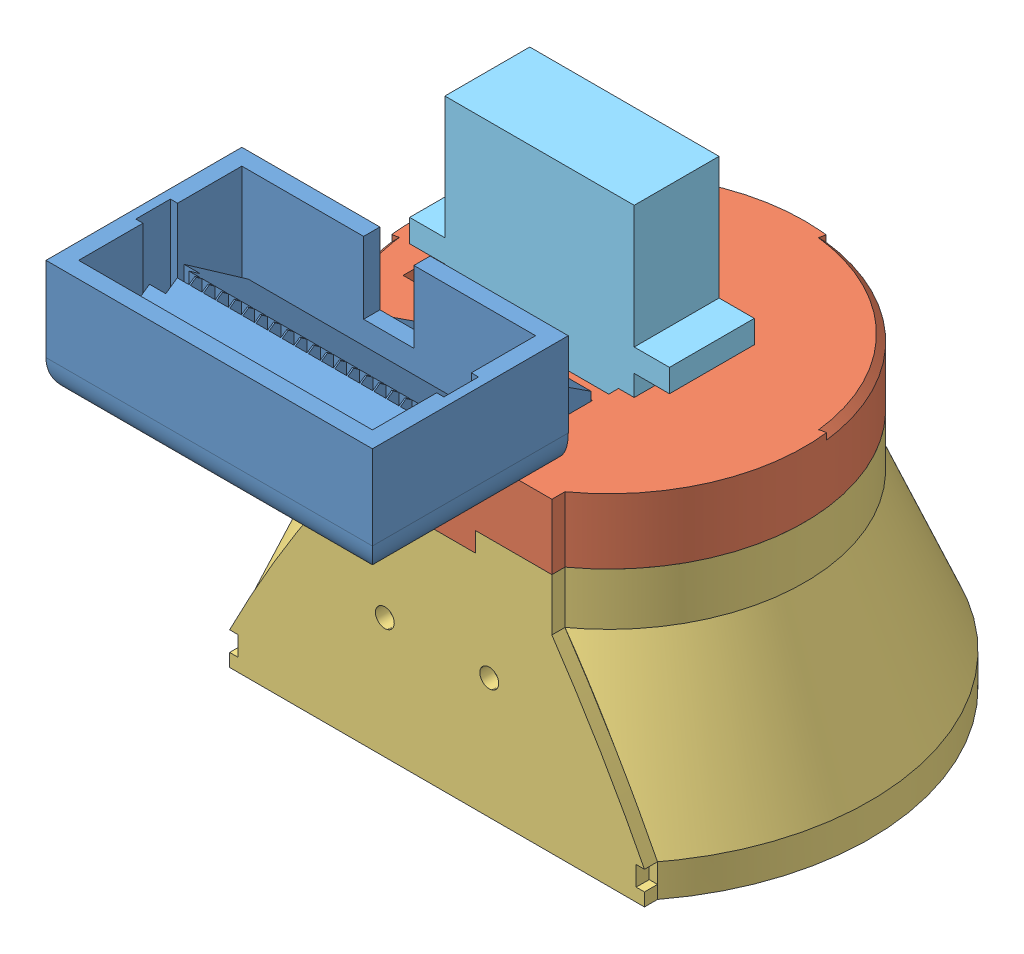
SolidWorks assembly funnelTrough, configuration Default. Lengths in mm.
Overall size (80 74.75 101.15).
5 component instances, 5 part files, 11 mates.
Components (placement in the parent):
- trough-1: trough [Default] at (-6.9672 -29.6533 -31.125) size (50.1 31 51.05)
- funnelMotorMount-1: funnelMotorMount [Default] at (-6.8672 -28.4033 -35.125) size (60 13.05 56.3)
- funnel-1: funnel [Default] at (-6.8672 -28.4033 -35.125) size (80 37 68.48)
- irShield-1: irShield [Default] at (10.2328 -3.1712 10.975) x (0 0 -1) z (1 0 0) size (5 3.9 2.54)
- servoOutline_micro-1: servoOutline_micro [Default] at (-10.9672 -7.9033 -28.625) x (0 0 -1) z (-1 0 0) size (13 35.3 39.8)
Mates (geometry in assembly coordinates):
- Coincident10: coincident: plane of trough-1 through (28.2088 -17.2758 -25.025) normal (0 0 -1); plane of funnelMotorMount-1 through (-6.8672 -21.6533 -25.025) normal (0 0 1)
- Coincident11: coincident: plane of trough-1 through (28.2088 -21.6533 -25.025) normal (0 -1 0); plane of funnelMotorMount-1 through (-6.8672 -21.6533 -35.125) normal (0 1 0)
- Coincident12: coincident: plane of trough-1 through (-14.4672 -12.1141 -15.2118) normal (-1 0 0); plane of funnelMotorMount-1 through (-14.4672 -21.6533 -35.125) normal (1 0 0)
- Coincident13: coincident: plane of funnelMotorMount-1 through (-6.8672 -28.4033 -35.125) normal (0 -1 0); plane of funnel-1 through (-6.8672 -28.4033 -35.125) normal (0 1 0)
- Coincident14: coincident: plane of funnelMotorMount-1 through (-0.9927 -31.4033 -8.825) normal (1 0 0); plane of funnel-1 through (-0.9927 -31.4033 -8.825) normal (-1 0 0)
- Coincident15: coincident: plane of funnelMotorMount-1 through (8.8746 -76.1936 -8.825) normal (0 0 1); plane of funnel-1 through (-175.0684 -162.3647 -8.825) normal (0 0 1)
- Parallel1: parallel: plane of trough-1 through (12.0328 -8.5533 10.975) normal (-1 0 0); plane of irShield-1 through (12.7728 -3.1712 10.975) normal (1 0 0)
- Coincident25: coincident: moEndPointRef_w of trough-1; moEndPointRef_w of irShield-1
- Coincident26: coincident: axis of funnelMotorMount-1 through (-6.8672 -28.4033 -35.125) axis (0 1 0); axis of servoOutline_micro-1 through (-6.8672 -28.2033 -35.125) axis (0 1 0)
- Coincident27: coincident: plane of funnelMotorMount-1 through (-6.8672 -22.9033 -35.125) normal (0 1 0); plane of servoOutline_micro-1 through (-10.9672 -22.9033 -41.625) normal (0 -1 0)
- Parallel2: parallel: plane of funnelMotorMount-1 through (1.1328 -22.9033 -43.125) normal (0 0 1); plane of servoOutline_micro-1 through (-10.9672 -7.9033 -41.625) normal (0 0 -1)
